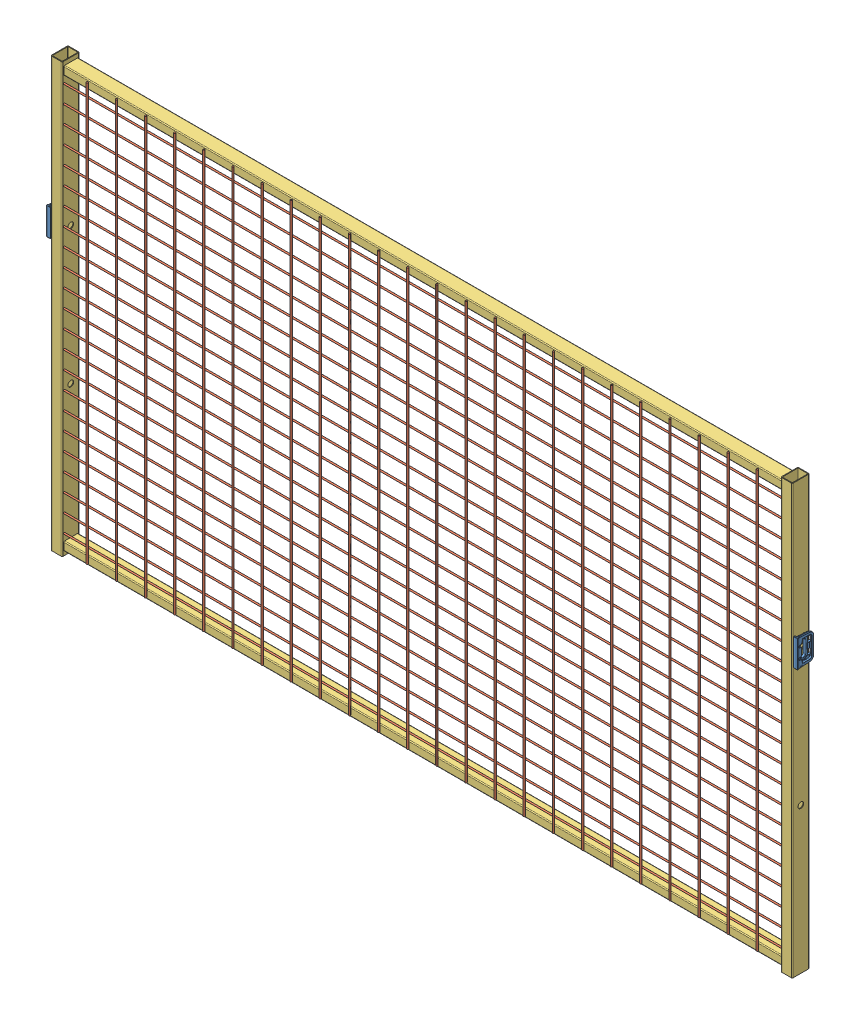
SolidWorks assembly W322-075130-Axelent, configuration Default. Lengths in mm.
Overall size (1315.63 750 30).
4 component instances, 3 part files, 0 mates.
Components (placement in the parent):
- G2032-1: G2032 [Default] at (-649 120 0) size (9.31 48.01 29.42)
- G2032-2: G2032 [Default] at (649 120 0) x (-1 0 0) z (0 0 1) size (9.31 48.01 29.42)
- NÄT-50x30_III_N-05030-075-130-1: NÄT-50x30_III_N-05030-075-130 [Default] at (0 0 13.5) x (-1 0 0) z (0 0 -1) size (1272 730 4.75)
- RAM-30_RAM-075-130-1: RAM-30_RAM-075-130 [Default] at origin size (1298 750 30)
